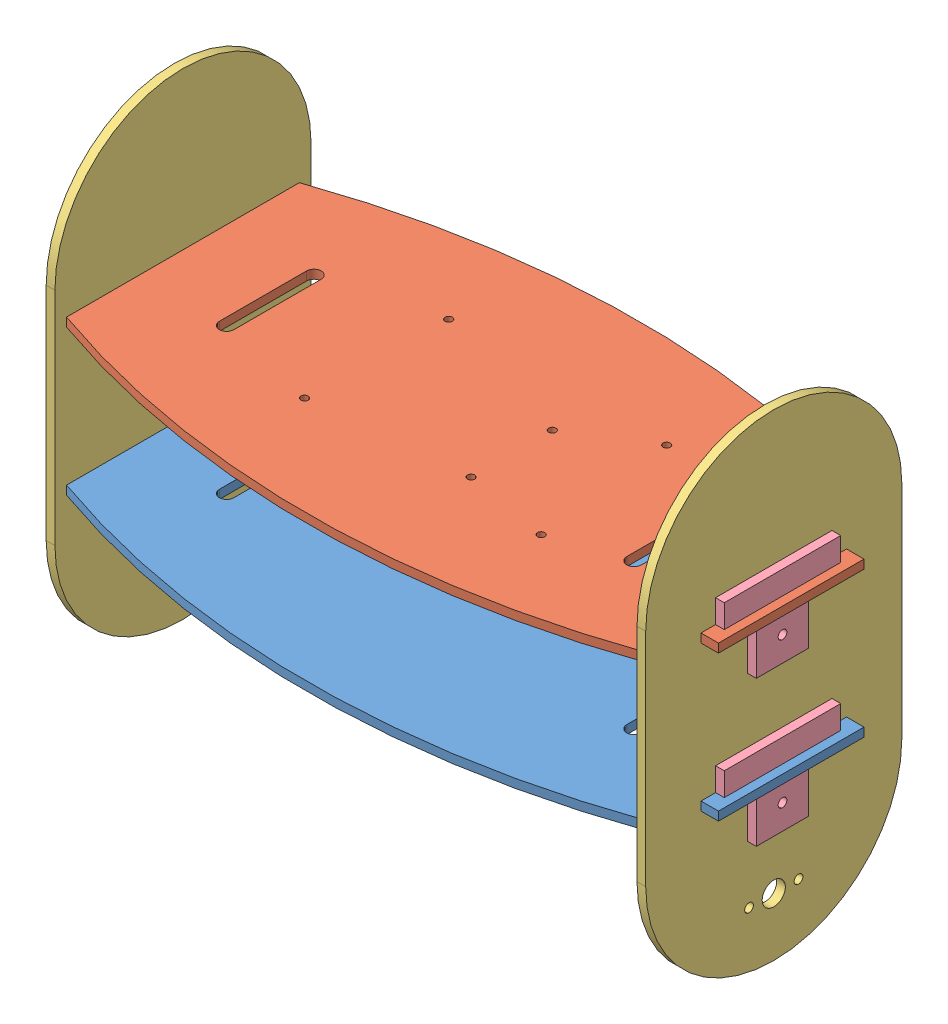
SolidWorks assembly Final Acrylic full robot - Copy, configuration Default. Lengths in mm.
Overall size (218 164 164.77).
8 component instances, 4 part files, 18 mates.
Components (placement in the parent):
- Final Acrylic body-1: Final Acrylic body [Default] at (135.5659 139.3996 253.2306) size (218 3 114.31)
- Final Acrylic body arduino-1: Final Acrylic body arduino [Default] at (135.5659 189.3996 253.2306) size (218 3 164.77)
- Acrylic side-1: Acrylic side [Default] at (235.5659 202.3996 253.2306) size (3 164 88)
- Acrylic side-2: Acrylic side [Default] at (32.5659 202.3996 253.2306) size (3 164 88)
- Acrylic T sec-1: Acrylic T sec [Default] at (241.5659 142.3996 253.2306) x (0 0 1) z (-1 0 0) size (40 28 3)
- Acrylic T sec-2: Acrylic T sec [Default] at (241.5659 192.3996 253.2306) x (0 0 1) z (-1 0 0) size (40 28 3)
- Acrylic T sec-3: Acrylic T sec [Default] at (32.5659 192.3996 253.2306) x (0 0 1) z (-1 0 0) size (40 28 3)
- Acrylic T sec-4: Acrylic T sec [Default] at (32.5659 142.3996 253.2306) x (0 0 1) z (-1 0 0) size (40 28 3)
Mates (geometry in assembly coordinates):
- Coincident2: coincident anti-aligned: plane of Final Acrylic body arduino-1 through (235.5659 192.3996 228.2306) normal (0 0 -1); plane of Acrylic side-1 through (238.5659 192.3996 228.2306) normal (0 0 1)
- Coincident3: coincident anti-aligned: plane of Final Acrylic body arduino-1 through (135.5659 192.3996 10.3879) normal (0 1 0); plane of Acrylic side-1 through (238.5659 192.3996 278.2306) normal (0 -1 0)
- Coincident4: coincident anti-aligned: plane of Final Acrylic body arduino-1 through (235.5659 192.3996 293.2306) normal (1 0 0); plane of Acrylic side-1 through (235.5659 202.3996 253.2306) normal (-1 0 0)
- Coincident5: coincident anti-aligned: plane of Final Acrylic body-1 through (235.5659 142.3996 278.2306) normal (0 0 1); plane of Acrylic side-1 through (238.5659 142.3996 278.2306) normal (0 0 -1)
- Coincident6: coincident anti-aligned: plane of Final Acrylic body-1 through (135.5659 139.3996 10.3879) normal (0 -1 0); plane of Acrylic side-1 through (238.5659 139.3996 228.2306) normal (0 1 0)
- Coincident7: coincident anti-aligned: plane of Final Acrylic body-1 through (235.5659 142.3996 293.2306) normal (1 0 0); plane of Acrylic side-1 through (235.5659 202.3996 253.2306) normal (-1 0 0)
- Coincident8: coincident anti-aligned: plane of Acrylic side-1 through (238.5659 202.3996 253.2306) normal (1 0 0); plane of Acrylic T sec-2 through (238.5659 192.3996 253.2306) normal (-1 0 0)
- Coincident9: coincident anti-aligned: plane of Acrylic side-1 through (238.5659 202.3996 253.2306) normal (1 0 0); plane of Acrylic T sec-1 through (238.5659 142.3996 253.2306) normal (-1 0 0)
- Concentric1: concentric anti-aligned: circle of Acrylic side-1; circle of Acrylic T sec-1
- Concentric2: concentric anti-aligned: circle of Acrylic side-1; circle of Acrylic T sec-2
- Coincident11: coincident anti-aligned: plane of Final Acrylic body-1 through (135.5659 139.3996 10.3879) normal (0 -1 0); plane of Acrylic side-2 through (35.5659 139.3996 228.2306) normal (0 1 0)
- Coincident12: coincident anti-aligned: plane of Final Acrylic body arduino-1 through (135.5659 192.3996 10.3879) normal (0 1 0); plane of Acrylic side-2 through (35.5659 192.3996 278.2306) normal (0 -1 0)
- Coincident13: coincident anti-aligned: plane of Final Acrylic body arduino-1 through (35.5659 192.3996 278.2306) normal (0 0 1); plane of Acrylic side-2 through (35.5659 192.3996 278.2306) normal (0 0 -1)
- Coincident14: coincident anti-aligned: plane of Final Acrylic body arduino-1 through (35.5659 192.3996 293.2306) normal (-1 0 0); plane of Acrylic side-2 through (35.5659 202.3996 253.2306) normal (1 0 0)
- Coincident15: coincident anti-aligned: plane of Acrylic side-2 through (32.5659 202.3996 253.2306) normal (-1 0 0); plane of Acrylic T sec-3 through (32.5659 192.3996 253.2306) normal (1 0 0)
- Coincident16: coincident anti-aligned: plane of Acrylic side-2 through (32.5659 202.3996 253.2306) normal (-1 0 0); plane of Acrylic T sec-4 through (32.5659 142.3996 253.2306) normal (1 0 0)
- Concentric3: concentric aligned: cylinder of Acrylic side-2 through (35.5659 130.8996 253.2306) axis (-1 0 0) radius 1.5; circle of Acrylic T sec-4
- Concentric4: concentric anti-aligned: circle of Acrylic side-2; circle of Acrylic T sec-3
